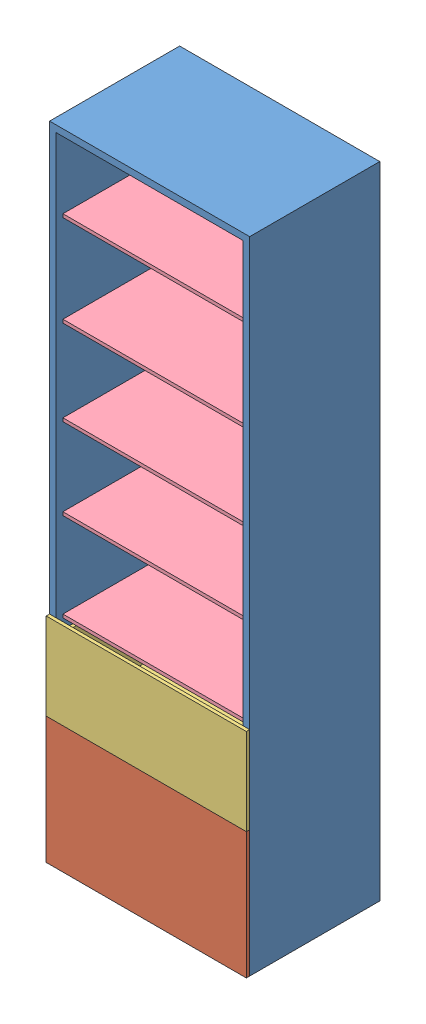
SolidWorks assembly Schrank-L, configuration Standard. Lengths in mm.
Overall size (600 1920 400).
8 component instances, 4 part files, 17 mates.
Components (placement in the parent):
- Schrank-Korpus-1: Schrank-Korpus [Standard] at (-405.9631 38.7369 1725) size (600 1920 390)
- Schublade-Hoch-1: Schublade-Hoch [Standard] at (-405.9631 -731.2631 2115) size (600 380 380)
- Schublade-Tief-1: Schublade-Tief [Standard] at (-405.9631 -411.2631 2115) size (600 260 380)
- Regalbrett-1: Regalbrett [Standard] at (-405.9631 -286.2631 1735) x (1 0 0) z (0 -1 0) size (560 360 10)
- Regalbrett-2: Regalbrett [Standard] at (-405.9631 -20.5713 1735) x (1 0 0) z (0 -1 0) size (560 360 10)
- Regalbrett-3: Regalbrett [Standard] at (-405.9631 223.3159 1735) x (1 0 0) z (0 -1 0) size (560 360 10)
- Regalbrett-4: Regalbrett [Standard] at (-405.9631 479.3348 1735) x (1 0 0) z (0 -1 0) size (560 360 10)
- Regalbrett-5: Regalbrett [Standard] at (-405.9631 753.23 1735) x (1 0 0) z (0 -1 0) size (560 360 10)
Mates (geometry in assembly coordinates):
- Deckungsgleich1: coincident anti-aligned: plane of Schrank-Korpus-1 through (-125.9631 978.7369 2115) normal (-1 0 0); plane of Schublade-Hoch-1 through (-125.9631 -901.2631 1755) normal (1 0 0)
- Deckungsgleich2: coincident anti-aligned: plane of Schrank-Korpus-1 through (-125.9631 978.7369 2115) normal (-1 0 0); plane of Schublade-Tief-1 through (-125.9631 -321.2631 1755) normal (1 0 0)
- Deckungsgleich3: coincident anti-aligned: plane of Schrank-Korpus-1 through (-405.9631 38.7369 1735) normal (0 0 1); plane of Regalbrett-1 through (-405.9631 -286.2631 1735) normal (0 0 -1)
- Deckungsgleich4: coincident aligned: plane of Schublade-Tief-1 through (-705.9631 -281.2631 2125) normal (0 1 0); plane of Regalbrett-1 through (-685.9631 -281.2631 2095) normal (0 1 0)
- Deckungsgleich5: coincident: plane of Schrank-Korpus-1 through (-405.9631 38.7369 1735) normal (0 0 1); plane of Regalbrett-2 through (-405.9631 -20.5713 1735) normal (0 0 -1)
- Deckungsgleich6: coincident: plane of Schrank-Korpus-1 through (-405.9631 38.7369 1735) normal (0 0 1); plane of Regalbrett-3 through (-405.9631 223.3159 1735) normal (0 0 -1)
- Deckungsgleich7: coincident: plane of Schrank-Korpus-1 through (-405.9631 38.7369 1735) normal (0 0 1); plane of Regalbrett-4 through (-405.9631 479.3348 1735) normal (0 0 -1)
- Deckungsgleich8: coincident: plane of Schrank-Korpus-1 through (-405.9631 38.7369 1735) normal (0 0 1); plane of Regalbrett-5 through (-405.9631 753.23 1735) normal (0 0 -1)
- Deckungsgleich9: coincident anti-aligned: plane of Schrank-Korpus-1 through (-685.9631 978.7369 2115) normal (1 0 0); plane of Regalbrett-5 through (-685.9631 748.23 2095) normal (-1 0 0)
- Deckungsgleich10: coincident anti-aligned: plane of Schrank-Korpus-1 through (-685.9631 978.7369 2115) normal (1 0 0); plane of Regalbrett-4 through (-685.9631 474.3348 2095) normal (-1 0 0)
- Deckungsgleich11: coincident anti-aligned: plane of Schrank-Korpus-1 through (-685.9631 978.7369 2115) normal (1 0 0); plane of Regalbrett-3 through (-685.9631 218.3159 2095) normal (-1 0 0)
- Deckungsgleich12: coincident anti-aligned: plane of Schrank-Korpus-1 through (-685.9631 978.7369 2115) normal (1 0 0); plane of Regalbrett-2 through (-685.9631 -25.5713 2095) normal (-1 0 0)
- Deckungsgleich13: coincident anti-aligned: plane of Schrank-Korpus-1 through (-685.9631 978.7369 2115) normal (1 0 0); plane of Regalbrett-1 through (-685.9631 -291.2631 2095) normal (-1 0 0)
- Deckungsgleich14: coincident anti-aligned: plane of Schrank-Korpus-1 through (-685.9631 -901.2631 2115) normal (0 1 0); plane of Schublade-Hoch-1 through (-685.9631 -901.2631 1755) normal (0 -1 0)
- Deckungsgleich15: coincident: line of Schublade-Hoch-1 through (-105.9631 -541.2631 2115) axis (-1 0 0); plane of Schublade-Tief-1 through (-705.9631 -541.2631 2125) normal (0 -1 0)
- Deckungsgleich16: coincident anti-aligned: plane of Schrank-Korpus-1 through (-405.9631 38.7369 2115) normal (0 0 1); plane of Schublade-Hoch-1 through (-405.9631 -731.2631 2115) normal (0 0 -1)
- Deckungsgleich17: coincident anti-aligned: plane of Schrank-Korpus-1 through (-405.9631 38.7369 2115) normal (0 0 1); plane of Schublade-Tief-1 through (-405.9631 -411.2631 2115) normal (0 0 -1)
